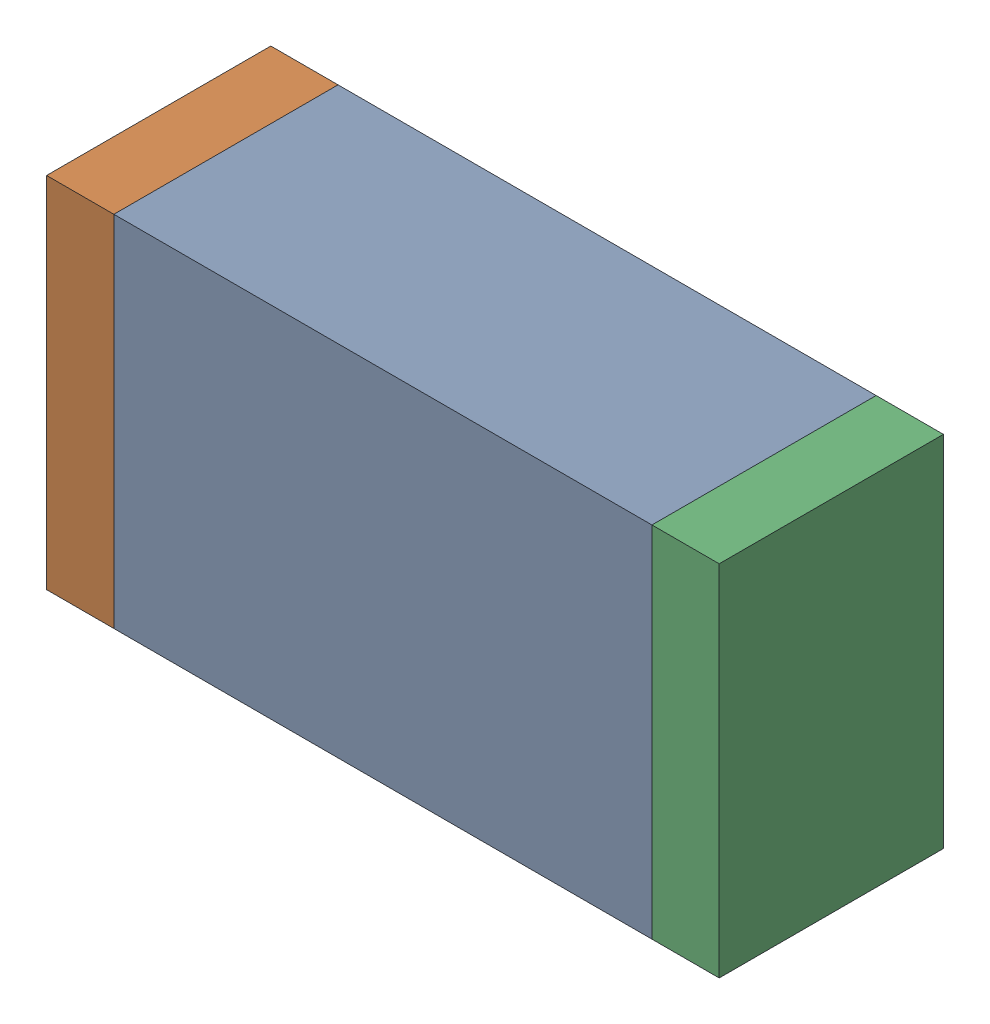
SolidWorks assembly R15, configuration Default. Lengths in mm.
Overall size (1.5 0.8 0.5).
6 component instances, 2 part files, 0 mates.
Components (placement in the parent):
- 836752368-1: 836752368 [Default] at (128 40.05 0) size (1.2 0.8 0.5)
  - Extruded-1: Extruded [Default] at origin size (1.2 0.8 0.5)
- 836752496-1: 836752496 [Default] at (127.325 40.05 0) size (0.15 0.8 0.5)
  - Extruded_2-1: Extruded_2 [Default] at origin size (0.15 0.8 0.5)
- 836752496-2: 836752496 [Default] at (128.675 40.05 0) size (0.15 0.8 0.5)
  - Extruded_2-1: Extruded_2 [Default] at origin size (0.15 0.8 0.5)
